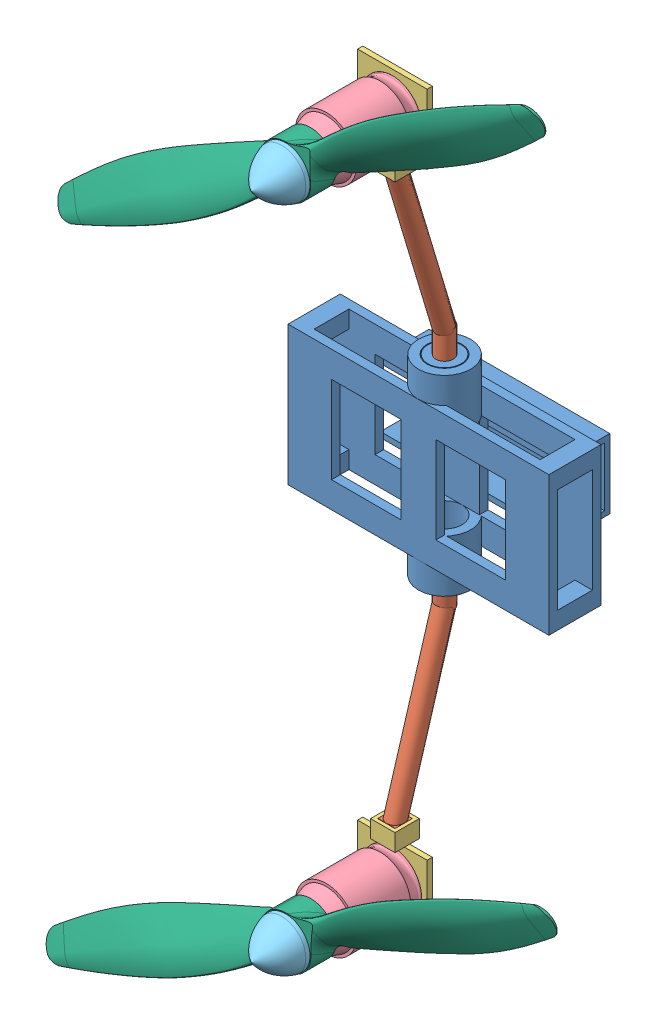
SolidWorks assembly Dron, configuration Varsayılan. Lengths in mm.
Overall size (304.84 579.7 154.37).
11 component instances, 6 part files, 17 mates.
Components (placement in the parent):
- şasi-1: şasi [Varsayılan] at (-25.717 16.9523 174) size (150 110 58)
- Motor uzatma-1: Motor uzatma [Varsayılan] at (-25.717 66.9523 164) x (-1 0 0) z (0 1 0) size (10.04 38.52 122)
- Motor uzatma-2: Motor uzatma [Varsayılan] at (-25.717 -33.0477 164) x (1 0 0) z (0 -1 0) size (10.04 38.52 122)
- motor prçası-1: motor prçası [Varsayılan] at (-25.717 178.9523 192.5187) x (-1 0 0) z (0 1 0) size (40 14 50)
- motor prçası-2: motor prçası [Varsayılan] at (-25.717 -145.0477 192.5187) x (1 0 0) z (0 -1 0) size (40 14 50)
- motor-1: motor [Varsayılan] at (-25.587 207.9506 222.2112) x (0 0 -1) z (0.991683 0.128706 0) size (64 35.2 35.2)
- motor-2: motor [Varsayılan] at (-25.787 -176.0554 222.2112) x (0 0 -1) z (0.997601 -0.069227 0) size (64 35.2 35.2)
- pervane ucu-1: pervane ucu [Varsayılan] at (-26.2035 201.687 269.2665) x (0 0 -1) z (-0.997766 0.066802 0) size (20 28 28)
- pervane ucu-2: pervane ucu [Varsayılan] at (-19.5167 -171.2296 269.2665) x (0 0 -1) z (0.524346 -0.851505 0) size (20 28 28)
- 13x6.5 pervane-1: 13x6.5 pervane [Varsayılan] at (-25.717 208.9523 239.1818) x (0.835718 0.549158 0) z (0.549158 -0.835718 0) size (331.01 27.97 29.88)
- 13x6.5 pervane-2: 13x6.5 pervane [Varsayılan] at (-25.717 -175.0477 239.1818) x (-0.877669 -0.479267 0) z (-0.479267 0.877669 0) size (331.01 27.97 29.88)
Mates (geometry in assembly coordinates):
- Eş Merkezli1: concentric aligned: circle of şasi-1; circle of Motor uzatma-1
- Çakışık2: coincident aligned: plane of şasi-1 through (-25.717 66.9523 164) normal (0 -1 0); plane of Motor uzatma-1 through (-25.717 66.9523 164) normal (0 -1 0)
- Paralel1: parallel aligned: plane of şasi-1 through (-25.717 16.9523 179) normal (0 0 1); plane of Motor uzatma-1 through (-20.717 188.9523 197.5187) normal (0 0 1)
- Çakışık4: coincident aligned: circle of şasi-1; circle of Motor uzatma-2
- Paralel2: parallel aligned: plane of şasi-1 through (-25.717 16.9523 179) normal (0 0 1); plane of Motor uzatma-2 through (-30.717 -155.0477 197.5187) normal (0 0 1)
- Çakışık5: coincident aligned: line of Motor uzatma-2 through (-30.717 -145.0477 197.3202) axis (0 0 -1); line of motor prçası-2 through (-30.717 -145.0477 197.5187) axis (0 0 -1)
- Çakışık6: coincident aligned: line of Motor uzatma-2 through (-23.3202 -145.0477 187.5187) axis (1 0 0); line of motor prçası-2 through (-30.717 -145.0477 187.5187) axis (1 0 0)
- Çakışık7: coincident aligned: line of Motor uzatma-1 through (-30.717 178.9523 192.1) axis (0 0 1); line of motor prçası-1 through (-30.717 178.9523 187.5187) axis (0 0 1)
- Çakışık8: coincident aligned: line of Motor uzatma-1 through (-20.717 178.9523 187.5187) axis (-1 0 0); line of motor prçası-1 through (-20.717 178.9523 187.5187) axis (-1 0 0)
- Eş Merkezli2: concentric anti-aligned: circle of motor prçası-1; circle of motor-1
- Çakışık9: coincident anti-aligned: plane of motor prçası-1 through (-5.717 228.9523 194.0187) normal (0 0 1); plane of motor-1 through (-27.8758 225.5853 194.0187) normal (0 0 -1)
- Eş Merkezli3: concentric anti-aligned: circle of motor prçası-2; circle of motor-2
- Çakışık10: coincident anti-aligned: plane of motor prçası-2 through (-45.717 -195.0477 194.0187) normal (0 0 1); plane of motor-2 through (-24.5559 -158.3155 194.0187) normal (0 0 -1)
- Çakışık11: coincident anti-aligned: circle of motor-2; circle of 13x6.5 pervane-2
- Çakışık12: coincident aligned: circle of pervane ucu-2; circle of 13x6.5 pervane-2
- Çakışık13: coincident anti-aligned: circle of motor-1; circle of 13x6.5 pervane-1
- Çakışık14: coincident aligned: circle of pervane ucu-1; circle of 13x6.5 pervane-1
